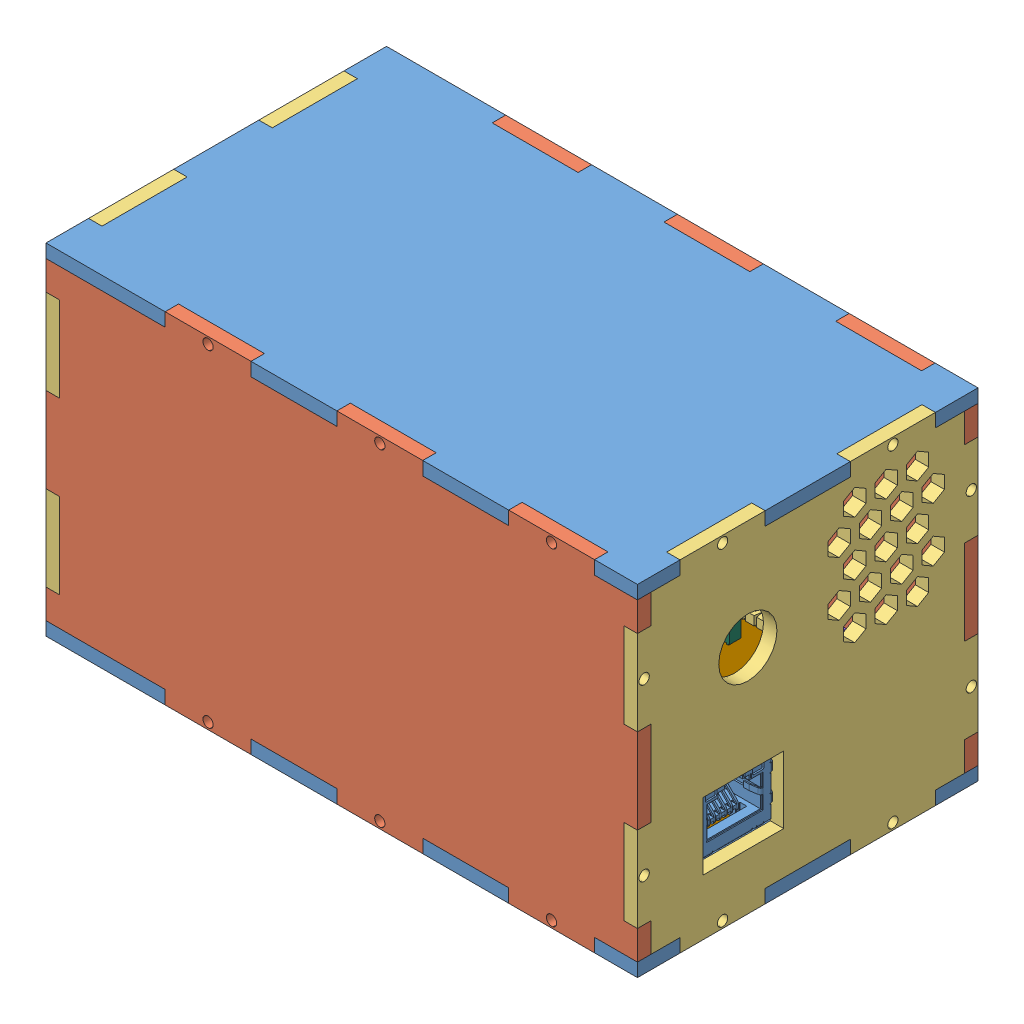
SolidWorks assembly Case, configuration Predeterminado. Lengths in mm.
Overall size (132 76 76).
37 component instances, 27 part files, 22 mates.
Components (placement in the parent):
- Bottom-1: Bottom [Bottom] at (0 -36.5 0) size (132 3 76)
- Bottom-2: Bottom [Top] at (0 36.5 0) size (132 3 76)
- longWall-1: longWall [Predeterminado] at (0 0 36.5) size (132 76 3)
- longWall-2: longWall [Predeterminado] at (0 0 -36.5) size (132 76 3)
- shortWall-1: shortWall [ETH] at (56 0 0) size (3 76 76)
- shortWall-2: shortWall [Power] at (-73 0 0) size (3 76 76)
- DE10_Nano_v3^Case-1: DE10_Nano_v3^Case [Predeterminado] at (-53.4 -26 34.295) x (1 0 0) z (0 1 0) size (110.71 68.59 19.41) (virtual)
  - ESQ-110-23-G-S^DE10_Nano_v3_Case-1: ESQ-110-23-G-S^DE10_Nano_v3_Case [Predeterminado] at origin size (25.91 2.54 18.41) (virtual)
    - _ESQ-110-23-G-S_socket^ESQ-110-23-G-S_DE10_Nano_v3_Case-1: _ESQ-110-23-G-S_socket^ESQ-110-23-G-S_DE10_Nano_v3_Case [Predeterminado] at (23.113 58.4222 6.5877) x (1 0 0) z (0 -1 0) size (25.91 8.51 2.41) (virtual)
    - _ESQ-110-23-G-S_pins^ESQ-110-23-G-S_DE10_Nano_v3_Case-1: _ESQ-110-23-G-S_pins^ESQ-110-23-G-S_DE10_Nano_v3_Case [Predeterminado] at (36.067 58.4222 6.5877) x (1 0 0) z (0 -1 0) size (25.15 14.85 2.16) (virtual)
    - _ESQ-110-23-G-S-LL_bpins^ESQ-110-23-G-S_DE10_Nano_v3_Case-1: _ESQ-110-23-G-S-LL_bpins^ESQ-110-23-G-S_DE10_Nano_v3_Case [Predeterminado] at (23.24 58.4222 1.5077) x (1 0 0) z (0 -1 0) size (25.4 5.08 2.54) (virtual)
  - ESW-106-23-G-S^DE10_Nano_v3_Case-1: ESW-106-23-G-S^DE10_Nano_v3_Case [Predeterminado] at origin size (15.75 2.54 15.88) (virtual)
    - _ESW-106-23-G-S_socket^ESW-106-23-G-S_DE10_Nano_v3_Case-1: _ESW-106-23-G-S_socket^ESW-106-23-G-S_DE10_Nano_v3_Case [Predeterminado] at (55.2064 10.1808 6.6404) x (1 0 0) z (0 -1 0) size (15.75 8.51 2.41) (virtual)
    - _ESW-106-23-G-S_pins^ESW-106-23-G-S_DE10_Nano_v3_Case-1: _ESW-106-23-G-S_pins^ESW-106-23-G-S_DE10_Nano_v3_Case [Predeterminado] at (63.0804 10.1808 6.6404) x (1 0 0) z (0 -1 0) size (14.99 12.31 2.16) (virtual)
    - _ESW-106-23-G-S_bsocket^ESW-106-23-G-S_DE10_Nano_v3_Case-1: _ESW-106-23-G-S_bsocket^ESW-106-23-G-S_DE10_Nano_v3_Case [Predeterminado] at (55.3461 10.1808 1.5604) x (1 0 0) z (0 -1 0) size (15.47 5.08 2.54) (virtual)
  - ESQ-108-24-T-S^DE10_Nano_v3_Case-1: ESQ-108-24-T-S^DE10_Nano_v3_Case [Predeterminado] at origin size (20.83 2.54 15.62) (virtual)
    - _ESQ-108-24-T-S_socket^ESQ-108-24-T-S_DE10_Nano_v3_Case-1: _ESQ-108-24-T-S_socket^ESQ-108-24-T-S_DE10_Nano_v3_Case [Predeterminado] at (32.2361 10.1512 6.5892) x (1 0 0) z (0 -1 0) size (20.83 8.51 2.41) (virtual)
    - _ESQ-108-24-T-S_pins^ESQ-108-24-T-S_DE10_Nano_v3_Case-1: _ESQ-108-24-T-S_pins^ESQ-108-24-T-S_DE10_Nano_v3_Case [Predeterminado] at (42.6501 10.1512 6.5892) x (1 0 0) z (0 -1 0) size (20.07 12.06 2.16) (virtual)
    - _ESQ-108-24-G-S-LL_bpins^ESQ-108-24-T-S_DE10_Nano_v3_Case-1: _ESQ-108-24-G-S-LL_bpins^ESQ-108-24-T-S_DE10_Nano_v3_Case [Predeterminado] at (32.3631 10.1512 1.5092) x (1 0 0) z (0 -1 0) size (20.32 5.08 2.54) (virtual)
  - ESQ-108-24-T-S_1^DE10_Nano_v3_Case-1: ESQ-108-24-T-S_1^DE10_Nano_v3_Case [Predeterminado] at (60.431 58.43 6.6) x (1 0 0) z (0 -1 0) size (20.83 15.62 2.54) (virtual)
    - _ESQ-108-24-T-S_socket^ESQ-108-24-T-S_1_DE10_Nano_v3_Case-1: _ESQ-108-24-T-S_socket^ESQ-108-24-T-S_1_DE10_Nano_v3_Case [Predeterminado] at (-10.414 0 0) size (20.83 8.51 2.41) (virtual)
    - _ESQ-108-24-T-S_pins^ESQ-108-24-T-S_1_DE10_Nano_v3_Case-1: _ESQ-108-24-T-S_pins^ESQ-108-24-T-S_1_DE10_Nano_v3_Case [Predeterminado] at origin size (20.07 12.06 2.16) (virtual)
    - _ESQ-108-24-G-S-LL_bpins^ESQ-108-24-T-S_1_DE10_Nano_v3_Case-1: _ESQ-108-24-G-S-LL_bpins^ESQ-108-24-T-S_1_DE10_Nano_v3_Case [Predeterminado] at (-10.287 -5.08 0) size (20.32 5.08 2.54) (virtual)
  - 10029449-111RLF^DE10_Nano_v3_Case-1: 10029449-111RLF^DE10_Nano_v3_Case [Predeterminado] at (5.3133 39.6183 4.9039) x (0 -1 0) z (0 0 -1) size (16.2 10.1 8.55) (virtual)
  - 548190519^DE10_Nano_v3_Case-1: 548190519^DE10_Nano_v3_Case [Predeterminado] at (-0.4947 22.0427 3.5001) x (0 -1 0) z (-1 0 0) size (7.7 5.76 9) (virtual)
  - CUI_DEVICES_PJ-002A^DE10_Nano_v3_Case-1: CUI_DEVICES_PJ-002A^DE10_Nano_v3_Case [Predeterminado] at (-1.7209 56.6595 8.0018) x (-1 0 0) z (0 1 0) size (14.4 14.5 9.4) (virtual)
  - 480251090^DE10_Nano_v3_Case-1: 480251090^DE10_Nano_v3_Case [Predeterminado] at (96.2566 19.9343 8.1358) x (0 1 0) z (1 0 0) size (18.53 18.25 25.43) (virtual)
  - 548190519^DE10_Nano_v3_Case-2: 548190519^DE10_Nano_v3_Case [Predeterminado] at (107.1706 42.7416 3.5101) x (0 1 0) z (1 0 0) size (7.7 5.76 9) (virtual)
  - 1050170001^DE10_Nano_v3_Case-1: 1050170001^DE10_Nano_v3_Case [Predeterminado] at (105.0827 57.1553 2.724) x (0 1 0) z (1 0 0) size (8.2 3.7 5.4) (virtual)
  - 901310780^DE10_Nano_v3_Case-1: 901310780^DE10_Nano_v3_Case [Predeterminado] at (47.8009 2.7952 3.0063) x (1 0 0) z (0 1 0) size (50.8 12.15 5.08) (virtual)
  - 901310780^DE10_Nano_v3_Case-2: 901310780^DE10_Nano_v3_Case [Predeterminado] at (47.372 65.7952 3.0063) x (1 0 0) z (0 1 0) size (50.8 12.15 5.08) (virtual)
  - 901310765^DE10_Nano_v3_Case-1: 901310765^DE10_Nano_v3_Case [Predeterminado] at (93.1104 3.0547 3.0149) x (1 0 0) z (0 1 0) size (12.7 12.15 5.08) (virtual)
  - DM3AT-SF-PEJM5^DE10_Nano_v3_Case-1: DM3AT-SF-PEJM5^DE10_Nano_v3_Case [Predeterminado] at (179.1499 -145.2 -0.0173) x (-1 0 0) z (0 0 -1) size (13.85 16.15 1.68) (virtual)
  - Component1^DE10_Nano_v3_Case-1: Component1^DE10_Nano_v3_Case [Predeterminado] at origin size (23 23 2.75) (virtual)
  - 21mm Heat sink^DE10_Nano_v3_Case-1: 21mm Heat sink^DE10_Nano_v3_Case [Predeterminado] at (44.2237 31.6386 4.25) size (21 21 11) (virtual)
  - SBH21-NBPN-D07-ST-BK--3DModel-STEP-56544^DE10_Nano_v3_Case-1: SBH21-NBPN-D07-ST-BK--3DModel-STEP-56544^DE10_Nano_v3_Case [Predeterminado] at (89.3414 65.2577 1.5) x (-1 0 0) z (0 1 0) size (21.3 8.4 5.4) (virtual)
  - DE10 Nano^DE10_Nano_v3_Case-1: DE10 Nano^DE10_Nano_v3_Case [Predeterminado] at origin size (106.92 68.59 1.5) (virtual)
Mates (geometry in assembly coordinates):
- Coincidente1: coincident aligned: plane of Bottom-1 through (0 -36.5 0) normal (0 0 1)
- Coincidente2: coincident aligned: plane of Bottom-1 through (0 -36.5 0) normal (1 0 0)
- Coincidente3: coincident aligned: plane of Bottom-1 through (0 -36.5 0) normal (0 0 1); plane of Bottom-2 through (0 36.5 0) normal (0 0 1)
- Coincidente4: coincident aligned: plane of Bottom-1 through (0 -36.5 0) normal (1 0 0); plane of Bottom-2 through (0 36.5 0) normal (1 0 0)
- Simétrico2: symmetric aligned: plane of Bottom-1 through (0 -35 0) normal (0 1 0); plane of Bottom-2 through (0 35 0) normal (0 -1 0)
- Coincidente6: coincident aligned: plane of Bottom-1 through (0 -36.5 0) normal (1 0 0); plane of longWall-1 through (0 0 36.5) normal (1 0 0)
- Coincidente7: coincident aligned: plane of longWall-1 through (0 0 36.5) normal (1 0 0); plane of longWall-2 through (0 0 -36.5) normal (1 0 0)
- Coincidente8: coincident aligned: plane of longWall-1 through (0 0 36.5) normal (0 1 0); plane of longWall-2 through (0 0 -36.5) normal (0 1 0)
- Coincidente9: coincident aligned: plane of longWall-2 through (0 0 -36.5) normal (0 1 0)
- Simétrico3: symmetric aligned: plane of longWall-1 through (0 0 35) normal (0 0 -1); plane of longWall-2 through (0 0 -35) normal (0 0 1)
- Coincidente12: coincident aligned: plane of Bottom-1 through (-57.5 -35 38) normal (0 0 1); plane of longWall-1 through (0 0 38) normal (0 0 1)
- Coincidente13: coincident anti-aligned: plane of Bottom-1 through (0 -35 0) normal (0 1 0); plane of longWall-1 through (-57.5 -35 38) normal (0 -1 0)
- Concéntrica1: concentric aligned: circle of Bottom-1; cylinder of DE10_Nano_v3^Case-1/DE10 Nano^DE10_Nano_v3_Case-1 through (50.22 -26 31.115) axis (0 1 0) radius 1.6
- Concéntrica2: concentric aligned: cylinder of Bottom-1 through (-50.22 -38 -31.115) axis (0 1 0) radius 1.2; cylinder of DE10_Nano_v3^Case-1/DE10 Nano^DE10_Nano_v3_Case-1 through (-50.22 -26 -31.115) axis (0 1 0) radius 1.6
- Distancia3: distance = 9 mm anti-aligned: plane of Bottom-1 through (0 -35 0) normal (0 1 0); plane of DE10_Nano_v3^Case-1/DE10 Nano^DE10_Nano_v3_Case-1 through (0.06 -26 0) normal (0 -1 0)
- Coincidente14: coincident aligned: plane of shortWall-1 through (56 0 0) normal (0 0 1); plane of shortWall-2 through (-73 0 0) normal (0 0 1)
- Coincidente15: coincident aligned: plane of shortWall-1 through (56 0 0) normal (0 1 0); plane of shortWall-2 through (-73 0 0) normal (0 1 0)
- Coincidente16: coincident aligned: plane of shortWall-1 through (56 0 0) normal (0 0 1)
- Coincidente17: coincident aligned: plane of shortWall-2 through (-73 0 0) normal (0 1 0)
- Simétrico5: symmetric aligned: plane of shortWall-1 through (53.5 0 0) normal (-1 0 0); plane of shortWall-2 through (-53.5 0 0) normal (1 0 0)
- Coincidente19: coincident aligned: plane of Bottom-1 through (57.5 -35 38) normal (1 0 0); plane of shortWall-1 through (57.5 0 0) normal (1 0 0)
- Coincidente21: coincident aligned: plane of Bottom-2 through (-74.5 36.5 0) normal (-1 0 0); plane of shortWall-2 through (-74.5 0 0) normal (-1 0 0)
